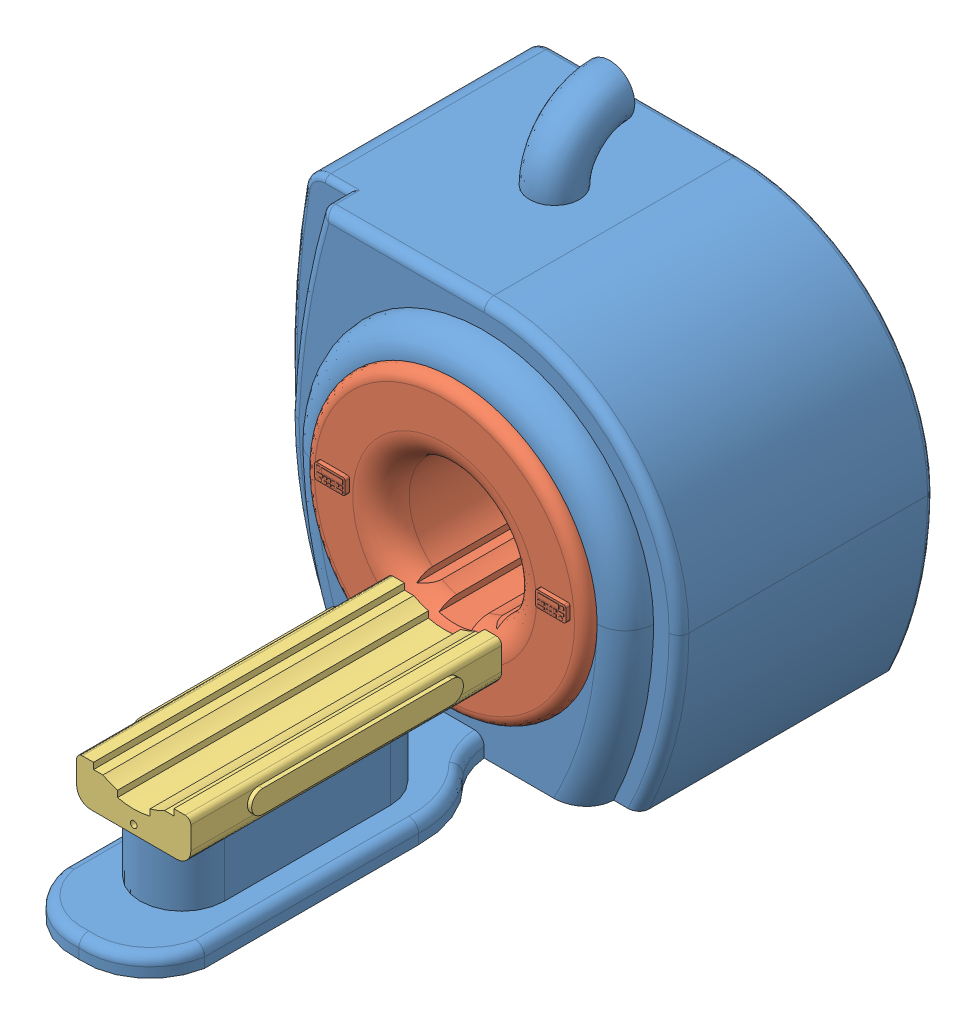
SolidWorks assembly MRI scanner, configuration Default. Lengths in mm.
Overall size (2298.25 2472.53 3646.55).
3 component instances, 3 part files, 6 mates.
Components (placement in the parent):
- Base Frame-1: Base Frame [Default] at (215.0742 187.8159 122.1083) size (2298.25 2472.53 3646.55)
- Center Part-1: Center Part [Default] at (370.4063 184.7421 93.4615) size (1560 1560 1647.36)
- Bed Base-1: Bed Base [Default] at (341.9747 -206.076 1751.6096) size (677.53 234 1716)
Mates (geometry in assembly coordinates):
- Coincident2: coincident aligned: line of Center Part-1 through (592.1727 -88.8504 848.9124) axis (0 0 -1); line of Bed Base-1 through (592.1727 -88.8504 2720.9124) axis (0 0 -1)
- Coincident3: coincident aligned: line of Center Part-1 through (148.6398 -88.8504 848.9124) axis (0 0 -1); line of Bed Base-1 through (148.6398 -88.8504 2720.9124) axis (0 0 -1)
- Coincident4: coincident: plane of Center Part-1 through (370.4063 183.2169 1004.9124) normal (0 0 1); plane of Bed Base-1 through (148.6398 -88.8504 1004.9124) normal (0 0 -1)
- Coincident5: coincident aligned: line of Bed Base-1 through (592.1727 -123.7993 2720.9124) axis (0 0 -1); line of ? through (592.1727 -123.7993 2705.2432) axis (0 0 -1)
- Coincident6: coincident aligned: line of Bed Base-1 through (148.6398 -123.7993 2720.9124) axis (0 0 -1); line of ? through (148.6398 -123.7993 2705.2432) axis (0 0 -1)
- Coincident7: coincident anti-aligned: circle of Base Frame-1; circle of Center Part-1
